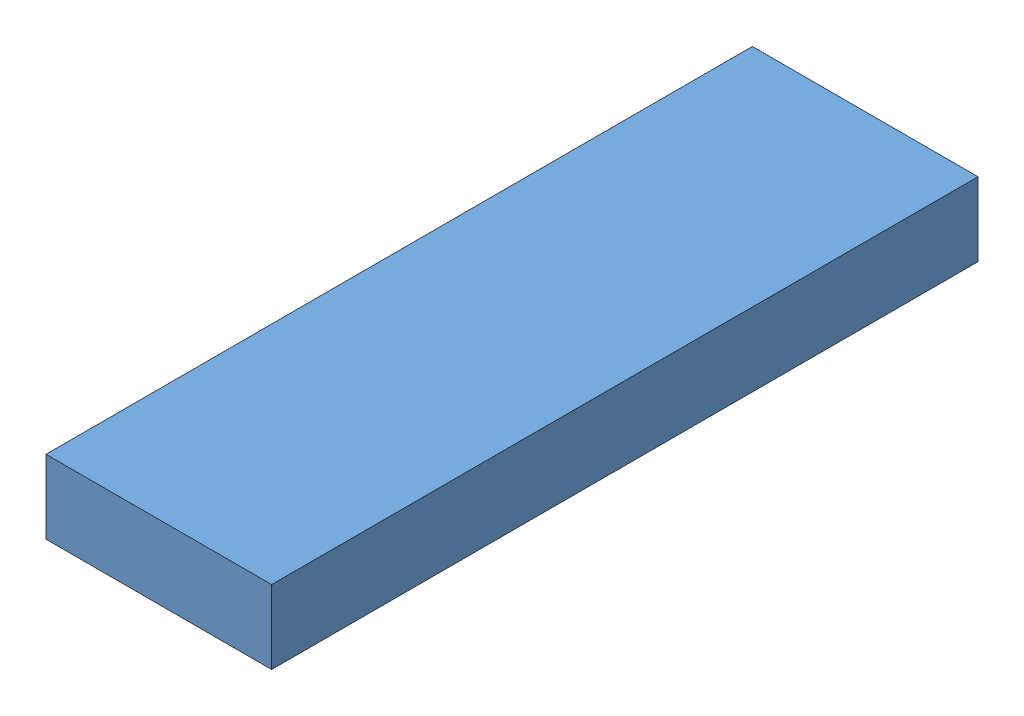
SolidWorks assembly cell_shim_pressurefixture_Aiden, configuration Default. Lengths in mm.
Overall size (56 19 154).
3 component instances, 2 part files, 7 mates.
Components (placement in the parent):
- SLPB8346143_cell_aiden-1: SLPB8346143_cell_aiden [15mm thick (max swell)] at origin size (46 15 144)
- Small_cellShimSLPB8346143_pressurefixture_Aiden-1: Small_cellShimSLPB8346143_pressurefixture_Aiden [Default] at (0 -2 0) size (56 2 154)
- Small_cellShimSLPB8346143_pressurefixture_Aiden-2: Small_cellShimSLPB8346143_pressurefixture_Aiden [Default] at (0 15 0) size (56 2 154)
Mates (geometry in assembly coordinates):
- Coincident1: coordinate: point of SLPB8346143_cell_aiden-1
- Coincident2: coincident aligned: plane of Small_cellShimSLPB8346143_pressurefixture_Aiden-1 through (0 -2 0) normal (1 0 0)
- Coincident3: coincident aligned: plane of Small_cellShimSLPB8346143_pressurefixture_Aiden-2 through (0 15 0) normal (1 0 0)
- Coincident4: coincident aligned: plane of Small_cellShimSLPB8346143_pressurefixture_Aiden-1 through (0 -2 0) normal (0 0 1)
- Coincident5: coincident aligned: plane of Small_cellShimSLPB8346143_pressurefixture_Aiden-2 through (0 15 0) normal (0 0 1)
- Coincident6: coincident anti-aligned: plane of SLPB8346143_cell_aiden-1 through (0 15 0) normal (0 1 0); plane of Small_cellShimSLPB8346143_pressurefixture_Aiden-2 through (0 15 0) normal (0 -1 0)
- Coincident7: coincident anti-aligned: plane of SLPB8346143_cell_aiden-1 through (0 0 0) normal (0 -1 0); plane of Small_cellShimSLPB8346143_pressurefixture_Aiden-1 through (0 0 0) normal (0 1 0)
